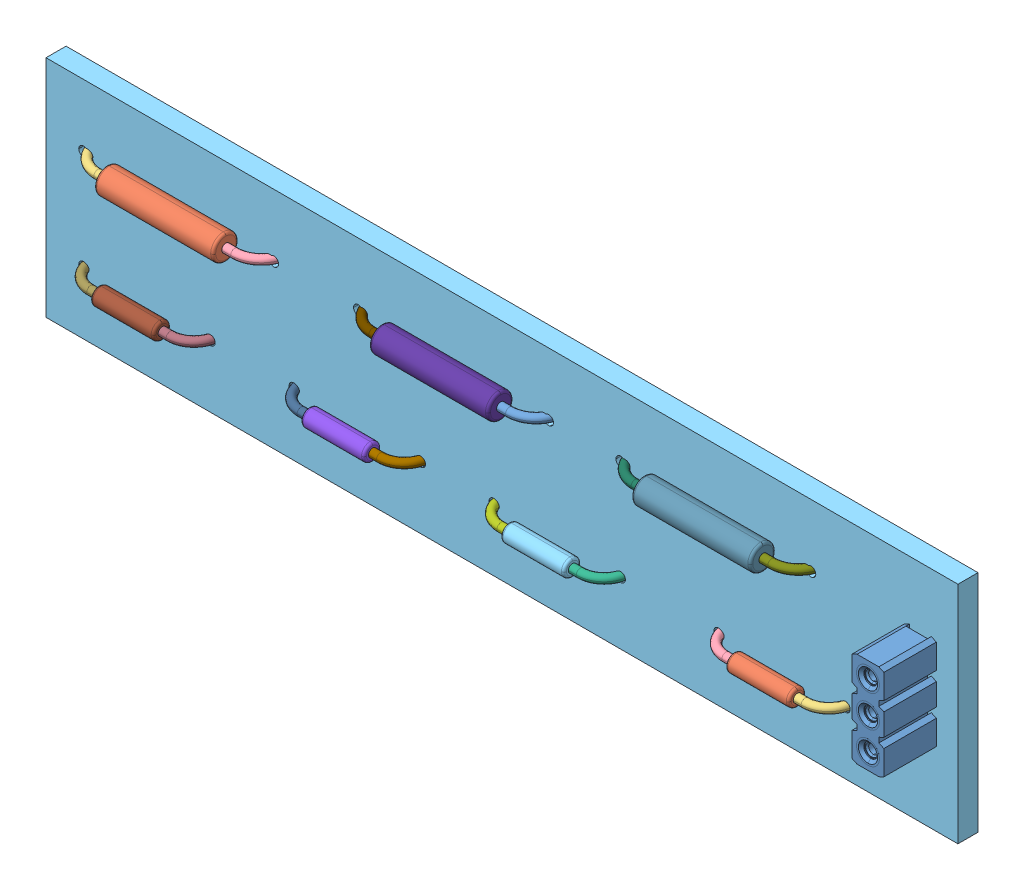
SolidWorks assembly Medicao_combustivel, configuration Valor predeterminado. Lengths in mm.
Overall size (73 18 7.53).
40 component instances, 23 part files, 0 mates.
Components (placement in the parent):
- Medicao_combustivel(2)^Medicao_combustivel-1: Medicao_combustivel(2)^Medicao_combustivel [Valor predeterminado] at origin size (73 18 7.53) (virtual)
  - J1^Medicao_combustivel(2)_Medicao_combustivel-1: J1^Medicao_combustivel(2)_Medicao_combustivel [Valor predeterminado] at (70 7 0.803) x (0 1 0) z (0 0 1) size (7.62 2.54 7.37) (virtual)
    - Open CASCADE STEP translator 6.8 2.2.1^J1_Medicao_combustivel(2)_Medicao_combustivel-1: Open CASCADE STEP translator 6.8 2.2.1^J1_Medicao_combustivel(2)_Medicao_combustivel [Valor predeterminado] at origin size (7.62 2.54 7.37) (virtual)
      - Body_1^Open CASCADE STEP translator 6.8 2.2.1_J1_Medicao_combustivel(2)_Medicao_combustivel-1: Body_1^Open CASCADE STEP translator 6.8 2.2.1_J1_Medicao_combustivel(2)_Medicao_combustivel [Valor predeterminado] at (2.5 0 0) x (1 0 0) z (0 -1 0) size (7.62 7.37 2.54) (virtual)
  - R1^Medicao_combustivel(2)_Medicao_combustivel-1: R1^Medicao_combustivel(2)_Medicao_combustivel [Valor predeterminado] at (64 5 0.803) x (-1 0 0) z (0 0 1) size (10.82 1.37 5.33) (virtual)
    - Open CASCADE STEP translator 6.8 2.3.1^R1_Medicao_combustivel(2)_Medicao_combustivel-1: Open CASCADE STEP translator 6.8 2.3.1^R1_Medicao_combustivel(2)_Medicao_combustivel [Valor predeterminado] at origin size (10.82 1.37 5.33) (virtual)
      - Body_1-0^Open CASCADE STEP translator 6.8 2.3.1_R1_Medicao_combustivel(2)_Medicao_combustivel-1: Body_1-0^Open CASCADE STEP translator 6.8 2.3.1_R1_Medicao_combustivel(2)_Medicao_combustivel [Valor predeterminado] at origin size (5.08 1.37 1.37) (virtual)
      - Pin_1^Open CASCADE STEP translator 6.8 2.3.1_R1_Medicao_combustivel(2)_Medicao_combustivel-1: Pin_1^Open CASCADE STEP translator 6.8 2.3.1_R1_Medicao_combustivel(2)_Medicao_combustivel [Valor predeterminado] at origin size (3.2 0.66 4.98) (virtual)
      - Pin_2^Open CASCADE STEP translator 6.8 2.3.1_R1_Medicao_combustivel(2)_Medicao_combustivel-1: Pin_2^Open CASCADE STEP translator 6.8 2.3.1_R1_Medicao_combustivel(2)_Medicao_combustivel [Valor predeterminado] at (20.32 0 0) x (-1 0 0) z (0 0 1) size (3.2 0.66 4.98) (virtual)
  - R2^Medicao_combustivel(2)_Medicao_combustivel-1: R2^Medicao_combustivel(2)_Medicao_combustivel [Valor predeterminado] at (46 5 0.803) x (-1 0 0) z (0 0 1) size (10.82 1.37 5.33) (virtual)
    - Open CASCADE STEP translator 6.8 2.3.1^R2_Medicao_combustivel(2)_Medicao_combustivel-1: Open CASCADE STEP translator 6.8 2.3.1^R2_Medicao_combustivel(2)_Medicao_combustivel [Valor predeterminado] at origin size (10.82 1.37 5.33) (virtual)
      - Body_1-0^Open CASCADE STEP translator 6.8 2.3.1_R2_Medicao_combustivel(2)_Medicao_combustivel-1: Body_1-0^Open CASCADE STEP translator 6.8 2.3.1_R2_Medicao_combustivel(2)_Medicao_combustivel [Valor predeterminado] at origin size (5.08 1.37 1.37) (virtual)
      - Pin_1^Open CASCADE STEP translator 6.8 2.3.1_R2_Medicao_combustivel(2)_Medicao_combustivel-1: Pin_1^Open CASCADE STEP translator 6.8 2.3.1_R2_Medicao_combustivel(2)_Medicao_combustivel [Valor predeterminado] at origin size (3.2 0.66 4.98) (virtual)
      - Pin_2^Open CASCADE STEP translator 6.8 2.3.1_R2_Medicao_combustivel(2)_Medicao_combustivel-1: Pin_2^Open CASCADE STEP translator 6.8 2.3.1_R2_Medicao_combustivel(2)_Medicao_combustivel [Valor predeterminado] at (20.32 0 0) x (-1 0 0) z (0 0 1) size (3.2 0.66 4.98) (virtual)
  - R3^Medicao_combustivel(2)_Medicao_combustivel-1: R3^Medicao_combustivel(2)_Medicao_combustivel [Valor predeterminado] at (30 5 0.803) x (-1 0 0) z (0 0 1) size (10.82 1.37 5.33) (virtual)
    - Open CASCADE STEP translator 6.8 2.3.1^R3_Medicao_combustivel(2)_Medicao_combustivel-1: Open CASCADE STEP translator 6.8 2.3.1^R3_Medicao_combustivel(2)_Medicao_combustivel [Valor predeterminado] at origin size (10.82 1.37 5.33) (virtual)
      - Body_1-0^Open CASCADE STEP translator 6.8 2.3.1_R3_Medicao_combustivel(2)_Medicao_combustivel-1: Body_1-0^Open CASCADE STEP translator 6.8 2.3.1_R3_Medicao_combustivel(2)_Medicao_combustivel [Valor predeterminado] at origin size (5.08 1.37 1.37) (virtual)
      - Pin_1^Open CASCADE STEP translator 6.8 2.3.1_R3_Medicao_combustivel(2)_Medicao_combustivel-1: Pin_1^Open CASCADE STEP translator 6.8 2.3.1_R3_Medicao_combustivel(2)_Medicao_combustivel [Valor predeterminado] at origin size (3.2 0.66 4.98) (virtual)
      - Pin_2^Open CASCADE STEP translator 6.8 2.3.1_R3_Medicao_combustivel(2)_Medicao_combustivel-1: Pin_2^Open CASCADE STEP translator 6.8 2.3.1_R3_Medicao_combustivel(2)_Medicao_combustivel [Valor predeterminado] at (20.32 0 0) x (-1 0 0) z (0 0 1) size (3.2 0.66 4.98) (virtual)
  - R4^Medicao_combustivel(2)_Medicao_combustivel-1: R4^Medicao_combustivel(2)_Medicao_combustivel [Valor predeterminado] at (3 5 0.803) size (10.82 1.37 5.33) (virtual)
    - Open CASCADE STEP translator 6.8 2.3.1^R4_Medicao_combustivel(2)_Medicao_combustivel-1: Open CASCADE STEP translator 6.8 2.3.1^R4_Medicao_combustivel(2)_Medicao_combustivel [Valor predeterminado] at origin size (10.82 1.37 5.33) (virtual)
      - Body_1-0^Open CASCADE STEP translator 6.8 2.3.1_R4_Medicao_combustivel(2)_Medicao_combustivel-1: Body_1-0^Open CASCADE STEP translator 6.8 2.3.1_R4_Medicao_combustivel(2)_Medicao_combustivel [Valor predeterminado] at origin size (5.08 1.37 1.37) (virtual)
      - Pin_1^Open CASCADE STEP translator 6.8 2.3.1_R4_Medicao_combustivel(2)_Medicao_combustivel-1: Pin_1^Open CASCADE STEP translator 6.8 2.3.1_R4_Medicao_combustivel(2)_Medicao_combustivel [Valor predeterminado] at origin size (3.2 0.66 4.98) (virtual)
      - Pin_2^Open CASCADE STEP translator 6.8 2.3.1_R4_Medicao_combustivel(2)_Medicao_combustivel-1: Pin_2^Open CASCADE STEP translator 6.8 2.3.1_R4_Medicao_combustivel(2)_Medicao_combustivel [Valor predeterminado] at (20.32 0 0) x (-1 0 0) z (0 0 1) size (3.2 0.66 4.98) (virtual)
  - REED1^Medicao_combustivel(2)_Medicao_combustivel-1: REED1^Medicao_combustivel(2)_Medicao_combustivel [Valor predeterminado] at (46 13 0.803) size (15.9 2.03 5.33) (virtual)
    - Open CASCADE STEP translator 6.8 2.7.1^REED1_Medicao_combustivel(2)_Medicao_combustivel-1: Open CASCADE STEP translator 6.8 2.7.1^REED1_Medicao_combustivel(2)_Medicao_combustivel [Valor predeterminado] at origin size (15.9 2.03 5.33) (virtual)
      - Body_1-1^Open CASCADE STEP translator 6.8 2.7.1_REED1_Medicao_combustivel(2)_Medicao_combustivel-1: Body_1-1^Open CASCADE STEP translator 6.8 2.7.1_REED1_Medicao_combustivel(2)_Medicao_combustivel [Valor predeterminado] at origin size (9.52 2.03 2.03) (virtual)
      - Pin_1-2^Open CASCADE STEP translator 6.8 2.7.1_REED1_Medicao_combustivel(2)_Medicao_combustivel-1: Pin_1-2^Open CASCADE STEP translator 6.8 2.7.1_REED1_Medicao_combustivel(2)_Medicao_combustivel [Valor predeterminado] at origin size (3.52 0.66 4.65) (virtual)
      - Pin_2-3^Open CASCADE STEP translator 6.8 2.7.1_REED1_Medicao_combustivel(2)_Medicao_combustivel-1: Pin_2-3^Open CASCADE STEP translator 6.8 2.7.1_REED1_Medicao_combustivel(2)_Medicao_combustivel [Valor predeterminado] at (30.48 0 0) x (-1 0 0) z (0 0 1) size (3.52 0.66 4.65) (virtual)
  - REED2^Medicao_combustivel(2)_Medicao_combustivel-1: REED2^Medicao_combustivel(2)_Medicao_combustivel [Valor predeterminado] at (25 13 0.803) size (15.9 2.03 5.33) (virtual)
    - Open CASCADE STEP translator 6.8 2.7.1^REED2_Medicao_combustivel(2)_Medicao_combustivel-1: Open CASCADE STEP translator 6.8 2.7.1^REED2_Medicao_combustivel(2)_Medicao_combustivel [Valor predeterminado] at origin size (15.9 2.03 5.33) (virtual)
      - Body_1-1^Open CASCADE STEP translator 6.8 2.7.1_REED2_Medicao_combustivel(2)_Medicao_combustivel-1: Body_1-1^Open CASCADE STEP translator 6.8 2.7.1_REED2_Medicao_combustivel(2)_Medicao_combustivel [Valor predeterminado] at origin size (9.52 2.03 2.03) (virtual)
      - Pin_1-2^Open CASCADE STEP translator 6.8 2.7.1_REED2_Medicao_combustivel(2)_Medicao_combustivel-1: Pin_1-2^Open CASCADE STEP translator 6.8 2.7.1_REED2_Medicao_combustivel(2)_Medicao_combustivel [Valor predeterminado] at origin size (3.52 0.66 4.65) (virtual)
      - Pin_2-3^Open CASCADE STEP translator 6.8 2.7.1_REED2_Medicao_combustivel(2)_Medicao_combustivel-1: Pin_2-3^Open CASCADE STEP translator 6.8 2.7.1_REED2_Medicao_combustivel(2)_Medicao_combustivel [Valor predeterminado] at (30.48 0 0) x (-1 0 0) z (0 0 1) size (3.52 0.66 4.65) (virtual)
  - REED3^Medicao_combustivel(2)_Medicao_combustivel-1: REED3^Medicao_combustivel(2)_Medicao_combustivel [Valor predeterminado] at (3 13 0.803) size (15.9 2.03 5.33) (virtual)
    - Open CASCADE STEP translator 6.8 2.7.1^REED3_Medicao_combustivel(2)_Medicao_combustivel-1: Open CASCADE STEP translator 6.8 2.7.1^REED3_Medicao_combustivel(2)_Medicao_combustivel [Valor predeterminado] at origin size (15.9 2.03 5.33) (virtual)
      - Body_1-1^Open CASCADE STEP translator 6.8 2.7.1_REED3_Medicao_combustivel(2)_Medicao_combustivel-1: Body_1-1^Open CASCADE STEP translator 6.8 2.7.1_REED3_Medicao_combustivel(2)_Medicao_combustivel [Valor predeterminado] at origin size (9.52 2.03 2.03) (virtual)
      - Pin_1-2^Open CASCADE STEP translator 6.8 2.7.1_REED3_Medicao_combustivel(2)_Medicao_combustivel-1: Pin_1-2^Open CASCADE STEP translator 6.8 2.7.1_REED3_Medicao_combustivel(2)_Medicao_combustivel [Valor predeterminado] at origin size (3.52 0.66 4.65) (virtual)
      - Pin_2-3^Open CASCADE STEP translator 6.8 2.7.1_REED3_Medicao_combustivel(2)_Medicao_combustivel-1: Pin_2-3^Open CASCADE STEP translator 6.8 2.7.1_REED3_Medicao_combustivel(2)_Medicao_combustivel [Valor predeterminado] at (30.48 0 0) x (-1 0 0) z (0 0 1) size (3.52 0.66 4.65) (virtual)
  - Placa_combustivel^Medicao_combustivel(2)_Medicao_combustivel-1: Placa_combustivel^Medicao_combustivel(2)_Medicao_combustivel [Valor predeterminado] at origin size (73 18 1.61) (virtual)
